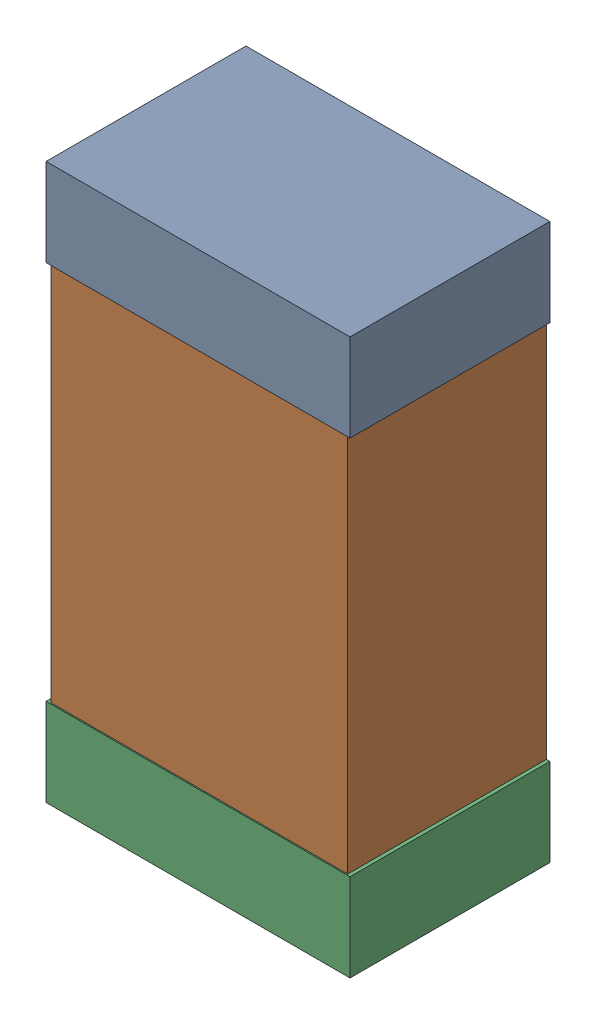
SolidWorks assembly ENBKanaloa_v2.0.0_Power, configuration Default. Lengths in mm.
Overall size (1.3 2.38 0.85).
6 component instances, 2 part files, 0 mates.
Components (placement in the parent):
- 330415056-1: 330415056 [Default] at (44.704 124.952 0) size (1.3 0.38 0.85)
  - Extruded_2-1: Extruded_2 [Default] at origin size (1.3 0.38 0.85)
- 352877008-1: 352877008 [Default] at (44.704 123.952 0) size (1.27 2.2 0.85)
  - Extruded_3-1: Extruded_3 [Default] at origin size (1.27 2.2 0.85)
- 330415056-2: 330415056 [Default] at (44.704 122.952 0) size (1.3 0.38 0.85)
  - Extruded_2-1: Extruded_2 [Default] at origin size (1.3 0.38 0.85)
